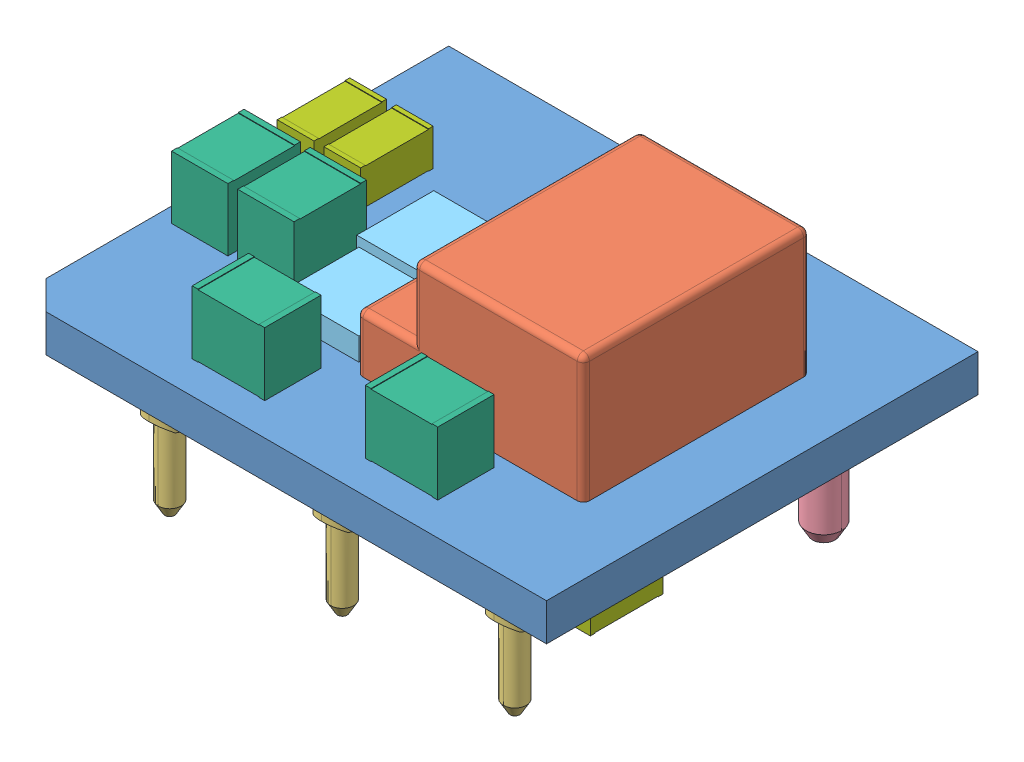
SolidWorks assembly i3a, configuration Default. Lengths in mm.
Overall size (23.38 13.24 19.05).
26 component instances, 9 part files, 3 mates.
Components (placement in the parent):
- i3a_full-1: i3a_full [Default] at (3.5174 2.2808 6.9359) x (1 0.000726 0) z (0 0 1) size (23.37 13.23 19.05)
  - i3a_standard_asm.stp-1: i3a_standard_asm.stp [Default] at origin size (23.37 13.23 19.05)
    - I3A_PCB.stp-1: I3A_PCB.stp [Default] at (-3.5174 0.0077 -6.974) x (1 -0.000726 0) z (0 0 1) size (23.37 1.65 19.05)
    - I3A_OUTPUT_INDUCTOR.stp-1: I3A_OUTPUT_INDUCTOR.stp [Default] at (0.2967 5.656 -6.9486) x (-1 0.000726 0) z (-0.000726 -1 0) size (10 10.01 5.6)
    - ZP00166_01-.stp-1: ZP00166_01-.stp [Default] at (-11.1374 0.0133 -0.116) x (0 0 1) z (1 -0.000726 0) size (1.83 6.99 1.83)
    - ZP00166_01-.stp-2: ZP00166_01-.stp [Default] at (-3.5174 0.0077 -0.116) x (0 0 1) z (1 -0.000726 0) size (1.83 6.99 1.83)
    - ZP00166_01-.stp-3: ZP00166_01-.stp [Default] at (4.1026 0.0022 -0.116) x (0 0 1) z (1 -0.000726 0) size (1.83 6.99 1.83)
    - ZP00167_01-.stp-1: ZP00167_01-.stp [Default] at (-11.1374 0.0133 -13.7558) x (1 -0.000726 0) z (0 0 -1) size (2.6 6.99 2.59)
    - ZP00167_01-.stp-2: ZP00167_01-.stp [Default] at (4.1026 0.0022 -13.7558) x (1 -0.000726 0) z (0 0 -1) size (2.6 6.99 2.59)
    - ZP00166_01-.stp-4: ZP00166_01-.stp [Default] at (-7.3274 0.0105 -13.7558) x (1 -0.000726 0) z (0 0 -1) size (1.83 6.99 1.83)
    - ZP00166_01-.stp-5: ZP00166_01-.stp [Default] at (-3.5174 0.0077 -13.7558) x (1 -0.000726 0) z (0 0 -1) size (1.83 6.99 1.83)
    - ZP00166_01-.stp-6: ZP00166_01-.stp [Default] at (0.2926 0.005 -13.7558) x (1 -0.000726 0) z (0 0 -1) size (1.83 6.99 1.83)
    - I6A_HIGH_SIDE_FET.stp-1: I6A_HIGH_SIDE_FET.stp [Default] at (-7.3008 1.6615 -7.9392) x (1 -0.000726 0) z (0 0 1) size (3.4 1 3.4)
    - I6A_HIGH_SIDE_FET.stp-2: I6A_HIGH_SIDE_FET.stp [Default] at (-6.7928 1.6611 -4.1292) x (1 -0.000726 0) z (0 0 1) size (3.4 1 3.4)
    - 1210_CAP_COLOR.stp-1: 1210_CAP_COLOR.stp [Default] at (-13.2902 1.6404 -5.196) x (0 0 1) z (-1 0.000726 0) size (3.2 2.79 2.49)
    - 1210_CAP_COLOR.stp-2: 1210_CAP_COLOR.stp [Default] at (-10.3702 1.6383 -5.196) x (0 0 1) z (-1 0.000726 0) size (3.2 2.79 2.49)
    - 1206_CAP_COLOR.stp-1: 1206_CAP_COLOR.stp [Default] at (-13.7302 1.6661 -9.869) x (0 0 1) z (-1 0.000726 0) size (3.2 1.63 1.63)
    - 1206_CAP_COLOR.stp-2: 1206_CAP_COLOR.stp [Default] at (-11.6702 1.6647 -9.869) x (0 0 1) z (-1 0.000726 0) size (3.2 1.63 1.63)
    - 1206_CAP_COLOR.stp-3: 1206_CAP_COLOR.stp [Default] at (-12.4613 0.0396 -11.139) x (1 -0.000726 0) z (0 0 -1) size (3.2 1.63 1.63)
    - 1206_CAP_COLOR.stp-4: 1206_CAP_COLOR.stp [Default] at (-12.4613 0.0396 -9.079) x (1 -0.000726 0) z (0 0 -1) size (3.2 1.63 1.63)
    - 1206_CAP_COLOR.stp-5: 1206_CAP_COLOR.stp [Default] at (-12.4613 0.0396 -7.019) x (1 -0.000726 0) z (0 0 -1) size (3.2 1.63 1.63)
    - 1206_CAP_COLOR.stp-6: 1206_CAP_COLOR.stp [Default] at (6.4186 0.0259 -1.919) x (0 0 1) z (1 -0.000726 0) size (3.2 1.63 1.63)
    - 0805_CAP.stp-1: 0805_CAP.stp [Default] at (5.6986 0.0264 -9.109) x (0 0 1) z (1 -0.000726 0) size (2.01 1.45 1.24)
    - I6A_CONTROL_IC2.stp-1: I6A_CONTROL_IC2.stp [Default] at (0.9786 0.0045 -8.089) x (0 0 -1) z (-1 0.000726 0) size (4.65 1 3.65)
    - 1210_CAP_COLOR.stp-3: 1210_CAP_COLOR.stp [Default] at (0.3198 1.6559 -0.139) x (1 -0.000726 0) z (0 0 1) size (3.2 2.79 2.49)
    - 1210_CAP_COLOR.stp-4: 1210_CAP_COLOR.stp [Default] at (-7.3002 1.6615 -0.119) x (1 -0.000726 0) z (0 0 1) size (3.2 2.79 2.49)
Mates (geometry in assembly coordinates):
- Coincident1: coincident: plane of ? through (0 2.2808 6.9359) normal (-1 0 0)
- Coincident2: coincident: plane of ? through (3.5174 2.2808 0) normal (0 0 -1)
- Coincident3: coincident: plane of ? through (3.5174 0 6.9359) normal (0 -1 0)
